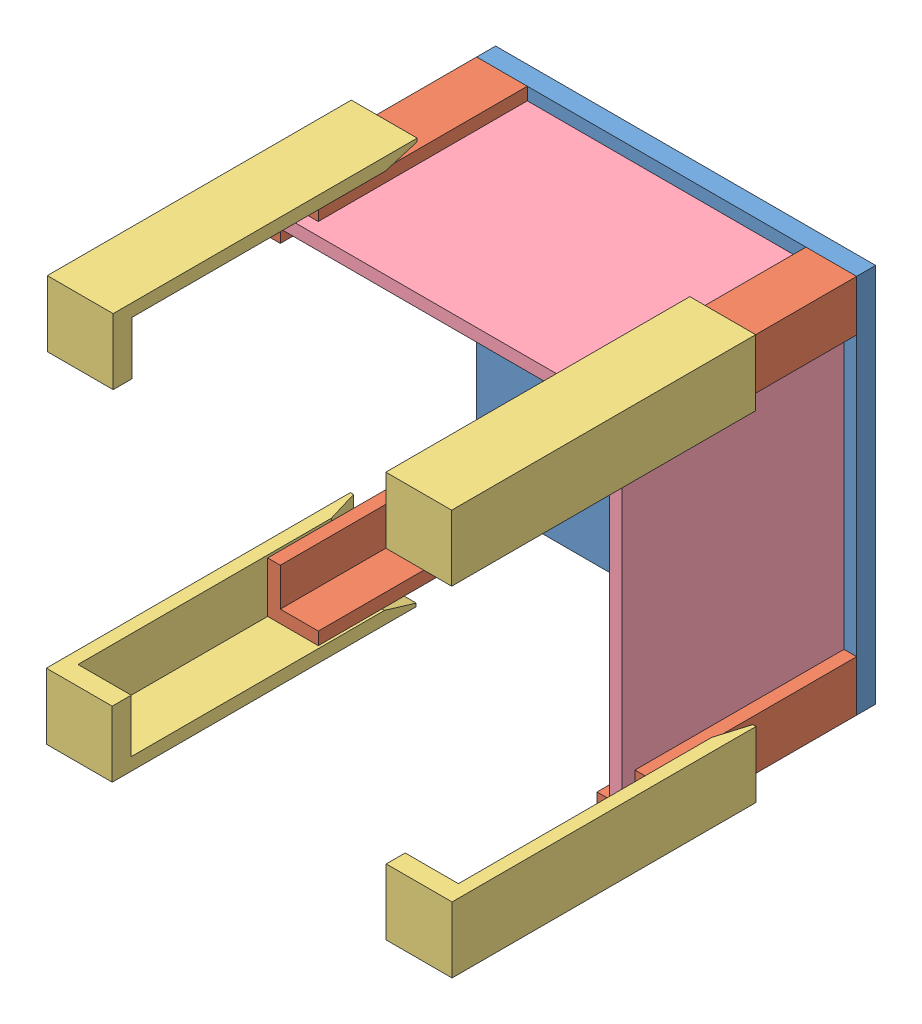
SolidWorks assembly Klebekäfig, configuration Standard. Lengths in mm.
Overall size (320 320 344.71).
11 component instances, 4 part files, 27 mates.
Components (placement in the parent):
- Käfigplatte-1: Käfigplatte [Standard] at (-149.6493 -140.8825 300) size (300 300 15)
- Käfigsäule-1: Käfigsäule [Standard] at (-149.6493 118.0672 422.7117) x (0 -1 0) z (1 0 0) size (40 165 40)
- Käfigsäule-3: Käfigsäule [Standard] at (-108.5991 -140.8825 422.7117) x (1 0 0) z (0 1 0) size (40 165 40)
- Käfigsäule-4: Käfigsäule [Standard] at (150.3507 -99.8323 422.7117) x (0 1 0) z (-1 0 0) size (40 165 40)
- Käfigsäule-5: Käfigsäule [Standard] at (109.3004 159.1175 422.7117) x (-1 0 0) z (0 -1 0) size (40 165 40)
- Führungssäule-1: Führungssäule [Standard] at (-159.6493 169.1175 643.9566) x (1 0 0) z (0 0 -1) size (52 52 240)
- Führungssäule-2: Führungssäule [Standard] at (160.3507 169.1175 644.7081) x (0 -1 0) z (0 0 -1) size (52 52 240)
- Führungssäule-3: Führungssäule [Standard] at (160.3507 -150.8825 644.4041) x (-1 0 0) z (0 0 -1) size (52 52 240)
- Führungssäule-4: Führungssäule [Standard] at (-159.6493 -150.8825 644.6999) x (0 1 0) z (0 0 -1) size (52 52 240)
- Seitenwände-7: Seitenwände [Standard] at (130.3507 149.1175 490) x (-1 0 0) z (0 -1 0) size (260 175 10)
- Seitenwände-8: Seitenwände [Standard] at (140.3507 -120.8825 490.1696) x (0 1 0) z (-1 0 0) size (260 175 10)
Mates (geometry in assembly coordinates):
- Deckungsgleich1: coincident anti-aligned: plane of Käfigplatte-1 through (-149.6493 -140.8825 315) normal (0 0 1); plane of Käfigsäule-1 through (-109.6493 159.1175 315) normal (0 0 -1)
- Deckungsgleich3: coincident aligned: plane of Käfigplatte-1 through (-149.6493 -140.8825 315) normal (-1 0 0); plane of Käfigsäule-1 through (-149.6493 118.0672 422.7117) normal (-1 0 0)
- Deckungsgleich4: coincident aligned: plane of Käfigplatte-1 through (-149.6493 159.1175 315) normal (0 1 0); plane of Käfigsäule-1 through (-109.6493 159.1175 315) normal (0 1 0)
- Deckungsgleich5: coincident anti-aligned: plane of Käfigplatte-1 through (-149.6493 -140.8825 315) normal (0 0 1); plane of Käfigsäule-3 through (-149.6493 -100.8825 315) normal (0 0 -1)
- Deckungsgleich6: coincident aligned: plane of Käfigplatte-1 through (-149.6493 -140.8825 315) normal (0 -1 0); plane of Käfigsäule-3 through (-108.5991 -140.8825 422.7117) normal (0 -1 0)
- Deckungsgleich7: coincident aligned: plane of Käfigplatte-1 through (-149.6493 -140.8825 315) normal (-1 0 0); plane of Käfigsäule-3 through (-149.6493 -100.8825 315) normal (-1 0 0)
- Deckungsgleich8: coincident anti-aligned: plane of Käfigplatte-1 through (-149.6493 -140.8825 315) normal (0 0 1); plane of Käfigsäule-4 through (110.3507 -140.8825 315) normal (0 0 -1)
- Deckungsgleich9: coincident aligned: plane of Käfigplatte-1 through (150.3507 -140.8825 315) normal (1 0 0); plane of Käfigsäule-4 through (150.3507 -99.8323 422.7117) normal (1 0 0)
- Deckungsgleich10: coincident aligned: plane of Käfigplatte-1 through (-149.6493 -140.8825 315) normal (0 -1 0); plane of Käfigsäule-4 through (110.3507 -140.8825 315) normal (0 -1 0)
- Deckungsgleich11: coincident: plane of Käfigplatte-1 through (-149.6493 -140.8825 315) normal (0 0 1); plane of Käfigsäule-5 through (150.3507 119.1175 315) normal (0 0 -1)
- Deckungsgleich12: coincident: plane of Käfigplatte-1 through (-149.6493 159.1175 315) normal (0 1 0); plane of Käfigsäule-5 through (109.3004 159.1175 422.7117) normal (0 1 0)
- Deckungsgleich13: coincident: plane of Käfigplatte-1 through (-149.6493 159.1175 315) normal (0 1 0); plane of Käfigsäule-5 through (109.3004 159.1175 422.7117) normal (0 1 0)
- Deckungsgleich14: coincident: plane of Käfigplatte-1 through (150.3507 -140.8825 315) normal (1 0 0); plane of Käfigsäule-5 through (150.3507 119.1175 315) normal (1 0 0)
- Deckungsgleich31: coincident anti-aligned: plane of Käfigsäule-1 through (-109.6493 159.1175 315) normal (0 1 0); plane of Führungssäule-1 through (-107.6493 159.1175 628.9566) normal (0 -1 0)
- Deckungsgleich32: coincident anti-aligned: plane of Käfigsäule-1 through (-149.6493 118.0672 422.7117) normal (-1 0 0); plane of Führungssäule-1 through (-149.6493 117.1175 628.9566) normal (1 0 0)
- Deckungsgleich34: coincident: plane of Käfigsäule-5 through (109.3004 159.1175 422.7117) normal (0 1 0); plane of Führungssäule-2 through (108.3507 159.1175 629.7081) normal (0 -1 0)
- Deckungsgleich36: coincident: plane of Käfigsäule-5 through (150.3507 119.1175 315) normal (1 0 0); plane of Führungssäule-2 through (150.3507 117.1175 629.7081) normal (-1 0 0)
- Deckungsgleich38: coincident anti-aligned: plane of Käfigsäule-4 through (150.3507 -99.8323 422.7117) normal (1 0 0); plane of Führungssäule-3 through (150.3507 -98.8825 629.4041) normal (-1 0 0)
- Deckungsgleich39: coincident anti-aligned: plane of Käfigsäule-4 through (110.3507 -140.8825 315) normal (0 -1 0); plane of Führungssäule-3 through (108.3507 -140.8825 629.4041) normal (0 1 0)
- Deckungsgleich42: coincident anti-aligned: plane of Käfigsäule-3 through (-108.5991 -140.8825 422.7117) normal (0 -1 0); plane of Führungssäule-4 through (-107.6493 -140.8825 629.6999) normal (0 1 0)
- Deckungsgleich43: coincident anti-aligned: plane of Käfigsäule-3 through (-149.6493 -100.8825 315) normal (-1 0 0); plane of Führungssäule-4 through (-149.6493 -98.8825 629.6999) normal (1 0 0)
- Deckungsgleich44: coincident: plane of Käfigsäule-1 through (-109.6493 118.0672 422.7117) normal (1 0 0); plane of Seitenwände-7 through (-109.6493 149.1175 325) normal (-1 0 0)
- Deckungsgleich45: coincident: plane of Käfigplatte-1 through (-149.6493 -140.8825 315) normal (0 0 1); plane of Seitenwände-7 through (130.3507 139.1175 315) normal (0 0 -1)
- Parallel2: parallel: plane of Käfigsäule-5 through (110.3507 119.1175 315) normal (-1 0 0); plane of Seitenwände-7 through (110.3507 149.1175 325) normal (1 0 0)
- Deckungsgleich48: coincident anti-aligned: plane of Käfigsäule-5 through (109.3004 149.1175 422.7117) normal (0 -1 0); plane of Seitenwände-7 through (130.3507 149.1175 490) normal (0 1 0)
- Deckungsgleich49: coincident: plane of Käfigsäule-5 through (109.3004 119.1175 422.7117) normal (0 -1 0); plane of Seitenwände-8 through (140.3507 119.1175 325.1696) normal (0 1 0)
- Deckungsgleich50: coincident anti-aligned: plane of Käfigsäule-5 through (140.3507 149.1175 480) normal (-1 0 0); plane of Seitenwände-8 through (140.3507 -120.8825 490.1696) normal (1 0 0)
